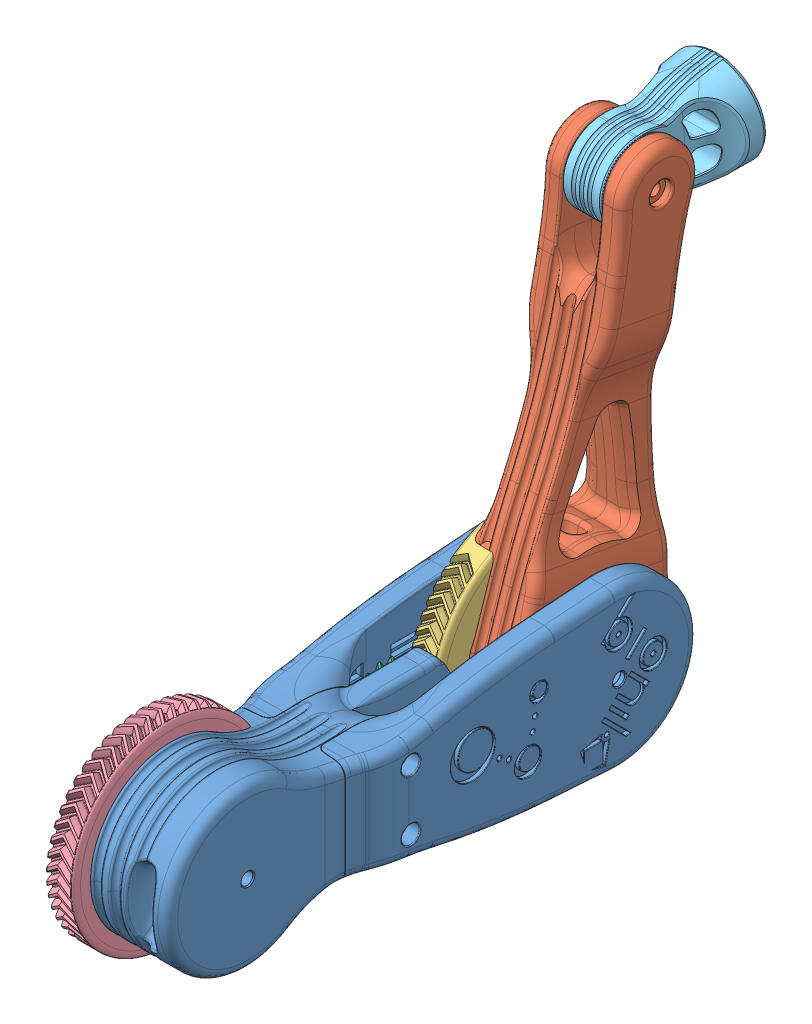
SolidWorks assembly 4-5 arm1-arm2, configuration Domyślna. Lengths in mm.
Overall size (91.84 292.34 314.31).
9 component instances, 8 part files, 16 mates.
Components (placement in the parent):
- 4 beta-1: 4 beta [Domyślna] at origin size (91.84 82.94 268.5)
- 5 Arm2-1: 5 Arm2 [Domyślna] at (0 0 -179) x (1 0 0) z (0 -0.984416 0.175858) size (70.01 82.39 258.96)
- 5.1.1.3 ISO - RH Helical gear 1.5M 57T 37HA 20PA 6FW ---57A75H50L56.0N-5: 5.1.1.3 ISO - RH Helical gear 1.5M 57T 37HA 20PA 6FW ---57A75H50L56.0N [ISO - RH Helical gear 1.5M 57T 37HA 20PA 6FW ---57A75H50L56.0N] at (-13 0 -179) x (1 0 0) z (0 -0.571736 0.820437) size (17.11 111.36 111.36)
- 4.1.3b ISO - RH Helical gear 1.5M 50T 37HA 20PA 6FW ---50A75H50L70.0N-1: 4.1.3b ISO - RH Helical gear 1.5M 50T 37HA 20PA 6FW ---50A75H50L70.0N [ISO - RH Helical gear 1.5M 50T 37HA 20PA 6FW ---50A75H50L70.0N] at (-20.5 0 0) x (1 0 0) z (0 0 -1) size (14.85 97.66 91.97)
- 5.1.3 Stamp-1: 5.1.3 Stamp [Domyślna] at (0 187.039 -212.413) x (1 0 0) z (0 -0.088917 0.996039) size (46.78 47.15 69.53)
- 4.2 MotorAssembly-1: 4.2 MotorAssembly [Domyślna] at (-30.05 0 -112.5682) x (0 0 1) z (-1 0 0) size (42 42 67.27)
  - 2.2.1 Nema 17 x 33-1: 2.2.1 Nema 17 x 33 [Default] at origin size (42 42 56.05) (hidden)
  - radiator-1: radiator [Domyślna] at (-0.0002 -0.0002 33) x (0 1 0) z (1 0 0) size (40.94 11 40.94) (hidden)
  - 4.2.2 ISO - LH Helical gear 1.5M 15T 37HA 20PA 6FW ---15A75H50L8.0N-1: 4.2.2 ISO - LH Helical gear 1.5M 15T 37HA 20PA 6FW ---15A75H50L8.0N [ISO - LH Helical gear 1.5M 15T 37HA 20PA 6FW ---15A75H50L8.0N] at (0 0 -23.05) x (0 0 1) z (-0.949504 0.313755 0) size (12.44 31.23 31.24)
Mates (geometry in assembly coordinates):
- Wspólnie1: coincident aligned: line of 4 beta-1 through (33 0 -179) axis (-1 0 0); line of 5 Arm2-1 through (33 0 -179) axis (-1 0 0)
- Wspólnie2: coincident aligned: plane of 4 beta-1 through (0 0 0) normal (1 0 0); plane of 5 Arm2-1 through (0 0 -179) normal (1 0 0)
- Wspólnie3: coincident anti-aligned: plane of 5 Arm2-1 through (-7 0 -179) normal (-1 0 0); plane of 5.1.1.3 ISO - RH Helical gear 1.5M 57T 37HA 20PA 6FW ---57A75H50L56.0N-5 through (-7 0 -179) normal (1 0 0)
- Koncentryczne1: concentric anti-aligned: cylinder of 5 Arm2-1 through (-19 0 -179) axis (1 0 0) radius 28; cylinder of 5.1.1.3 ISO - RH Helical gear 1.5M 57T 37HA 20PA 6FW ---57A75H50L56.0N-5 through (49.5 0 -179) axis (-1 0 0) radius 28
- Wspólnie4: coincident anti-aligned: plane of 5 Arm2-1 through (-19 -14.2934 -158.4891) normal (0 -0.571736 0.820437); plane of 5.1.1.3 ISO - RH Helical gear 1.5M 57T 37HA 20PA 6FW ---57A75H50L56.0N-5 through (-19 -34.8043 -172.7825) normal (0 0.571736 -0.820437)
- Wspólnie5: coincident anti-aligned: plane of 4 beta-1 through (-14.5 0 0) normal (-1 0 0); plane of 4.1.3b ISO - RH Helical gear 1.5M 50T 37HA 20PA 6FW ---50A75H50L70.0N-1 through (-14.5 0 0) normal (1 0 0)
- Koncentryczne3: concentric anti-aligned: cylinder of 4 beta-1 through (-33 0 0) axis (1 0 0) radius 3; cylinder of 4.1.3b ISO - RH Helical gear 1.5M 50T 37HA 20PA 6FW ---50A75H50L70.0N-1 through (42 0 0) axis (-1 0 0) radius 35
- Koncentryczne2: concentric aligned: cylinder of 5 Arm2-1 through (-20.625 187.039 -212.413) axis (1 0 0) radius 2.9; cylinder of 5.1.3 Stamp-1 through (-23.393 187.039 -212.413) axis (1 0 0) radius 3.75
- Wspólnie7: coincident aligned: plane of 5.1.3 Stamp-1 through (0 187.039 -212.413) normal (1 0 0); plane of assembly through (0 0 0) normal (1 0 0)
- Wspólnie8: coincident aligned: plane of 4 beta-1 through (0 0 0) normal (1 0 0); plane of assembly through (0 0 0) normal (1 0 0)
- Wspólnie9: coordinate: point of 4 beta-1; point of assembly
- Równolegle1: parallel anti-aligned: plane of 4.2 MotorAssembly-1/2.2.1 Nema 17 x 33-1 through (-30.05 0 -112.5682) normal (-1 0 0); plane of assembly through (0 0 0) normal (1 0 0)
- Wspólnie10: coincident aligned: plane of 4.2 MotorAssembly-1/2.2.1 Nema 17 x 33-1 through (-30.05 0 -112.5682) normal (0 1 0); plane of assembly through (0 0 0) normal (0 1 0)
- Wspólnie11: coincident aligned: plane of 5.1.1.3 ISO - RH Helical gear 1.5M 57T 37HA 20PA 6FW ---57A75H50L56.0N-5 through (-19 0 -179) normal (-1 0 0); plane of 4.2 MotorAssembly-1/4.2.2 ISO - LH Helical gear 1.5M 15T 37HA 20PA 6FW ---15A75H50L8.0N-1 through (-19 0 -112.5682) normal (-1 0 0)
- Szczelina1: slot aligned: cylinder of 4.2 MotorAssembly-1/2.2.1 Nema 17 x 33-1 through (-28.75 0 -112.5682) axis (-1 0 0) radius 11; cylinder of 4 beta-1 through (33 0 -116) axis (-1 0 0) radius 11.1; cylinder of 4 beta-1 through (33 0 -106) axis (-1 0 0) radius 11.1
- Wspólnie12: coincident anti-aligned: plane of 4.1.3b ISO - RH Helical gear 1.5M 50T 37HA 20PA 6FW ---50A75H50L70.0N-1 through (9.9605 12.1967 12.1967) normal (0 -0.707107 -0.707107); plane of 4 beta-1 through (-26.5 12.1967 12.1967) normal (0 0.707107 0.707107)
